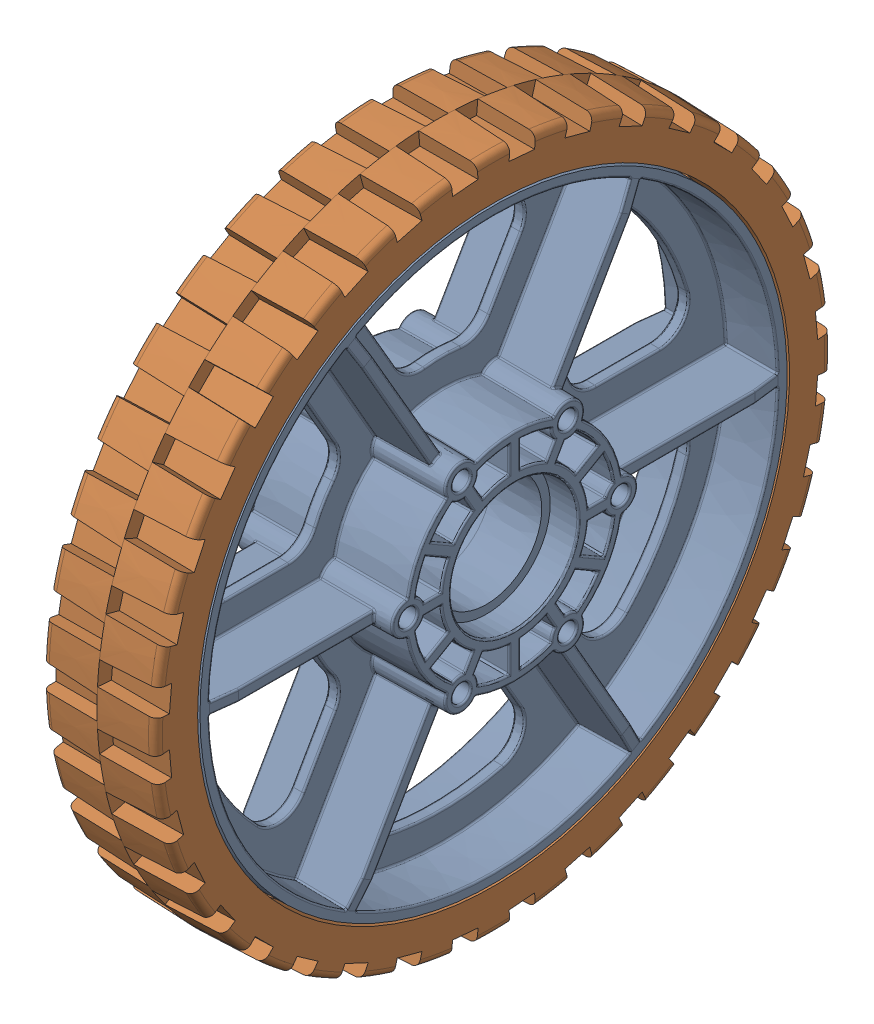
SolidWorks assembly 6 HiGrip Asm Rev II, configuration Default. Lengths in mm.
Overall size (34.93 152.4 152.4).
2 component instances, 2 part files, 0 mates.
Components (placement in the parent):
- 6 wheel Rev 4-1: 6 wheel Rev 4 [Default] at (-52.6446 9.4231 21.378) size (34.93 132.08 132.08)
- 6 wheel tread II-1: 6 wheel tread II [Default] at (-65.3446 9.4231 21.378) x (0 0 -1) z (1 0 0) size (152.4 152.4 25.58)
